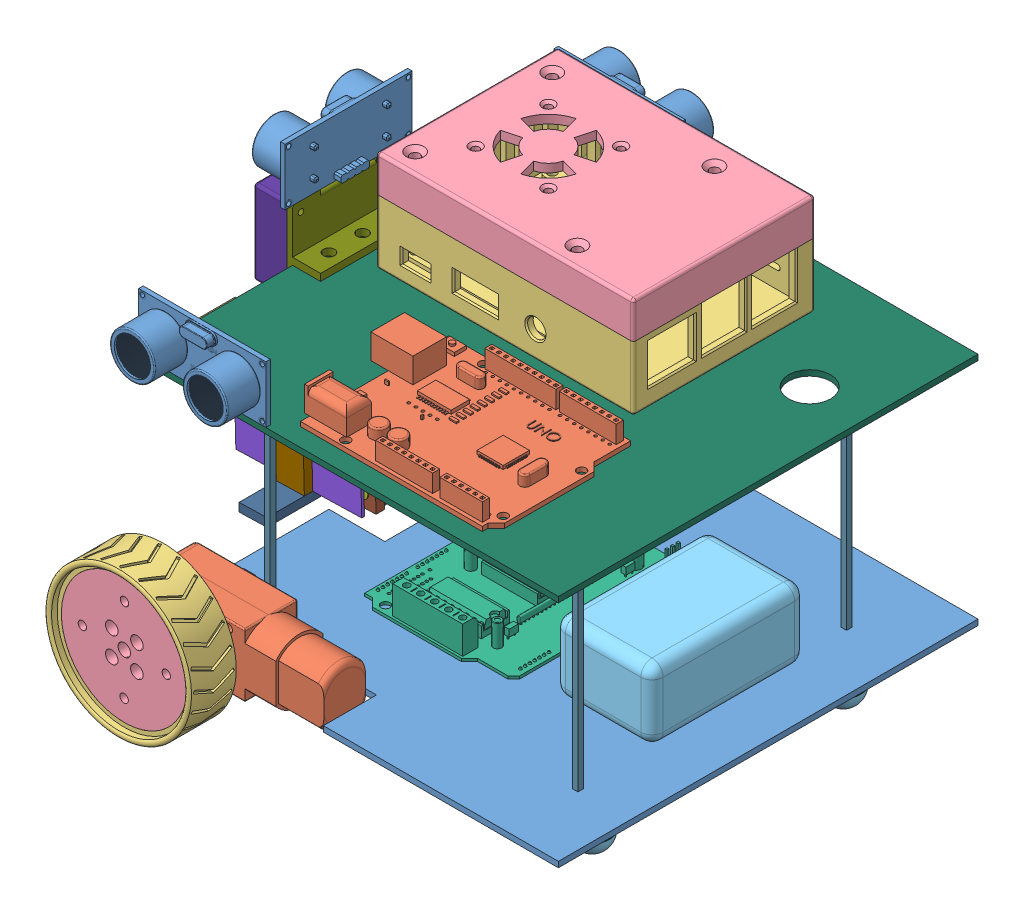
SolidWorks assembly Robo, configuration Default. Lengths in mm.
Overall size (198.95 162.78 193.09).
44 component instances, 24 part files, 52 mates.
Components (placement in the parent):
- Chassie-1: Chassie [Default] at (56.3992 70.6772 119.4071) size (150 2 150)
- wheel-1: wheel [Default] at (-59.9248 68.2072 35.5851) x (0 0 -1) z (0.96637 0.257157 0) size (47.16 66.76 87.56)
  - dc_motor_with_wheel-1: dc_motor_with_wheel [Défaut] at origin size (37.6 36.38 67.23)
  - tyre-1: tyre [Default] at (1.5267 -5.0802 53) x (1 0 0) z (0 0.34528 0.9385) size (16.83 52 52)
  - wheel_3wholes_outerlayer-1: wheel_3wholes_outerlayer [Default] at (7.5267 -5.0802 53) x (0 -0.603955 0.797018) z (0 -0.797018 -0.603955) size (45 4 45)
- wheel-2: wheel [Default] at (-59.9248 85.6472 203.229) x (0 0 1) z (0.96637 -0.257157 0) size (47.16 66.76 87.56)
  - dc_motor_with_wheel-1: dc_motor_with_wheel [Défaut] at origin size (37.6 36.38 67.23)
  - tyre-1: tyre [Default] at (1.5267 -5.0802 53) x (1 0 0) z (0 0.34528 0.9385) size (16.83 52 52)
  - wheel_3wholes_outerlayer-1: wheel_3wholes_outerlayer [Default] at (7.5267 -5.0802 53) x (0 -0.603955 0.797018) z (0 -0.797018 -0.603955) size (45 4 45)
- ball_v2-1: ball_v2 [Default] at (114.5561 64.9929 70.0782) x (-0.994727 0.101202 0.016649) z (0.102116 0.992387 0.068845) size (19.98 29.54 22.65)
  - ball-1: ball [Predeterminado] at (1.5642 3.9174 -7.4116) x (0.97009 -0.147809 -0.192554) z (0.182549 -0.078633 0.980047) size (12.6 12.6 12.6)
  - bas-1: bas [Predeterminado] at (3.6231 4.1003 3.995) x (-0.016649 -0.997488 -0.068845) z (0.994727 -0.009555 -0.102116) size (28.57 12.2 18.37)
- ball_v2-2: ball_v2 [Default] at (114.5561 64.9929 159.8852) x (-0.994727 0.101202 0.016649) z (0.102116 0.992387 0.068845) size (19.98 29.54 22.65)
  - ball-1: ball [Predeterminado] at (1.5642 3.9174 -7.4116) x (0.97009 -0.147809 -0.192554) z (0.182549 -0.078633 0.980047) size (12.6 12.6 12.6)
  - bas-1: bas [Predeterminado] at (3.6231 4.1003 3.995) x (-0.016649 -0.997488 -0.068845) z (0.994727 -0.009555 -0.102116) size (28.57 12.2 18.37)
- gripper-1: gripper [Default] at (95.6972 294.7422 312.9195) x (0.383049 0 0.923728) z (0 -1 0) size (92.65 69.09 65.38)
  - Servo-1: Servo [Default] at (-244.1629 10.2538 215.865) x (0.383049 -0.923728 0) z (0 0 1) size (27.6 29.9 12.4)
  - pad-1: pad [Default] at (-243.8055 16.9469 180.3776) x (-0.010204 0.024608 -0.999645) z (-0.923728 -0.383049 0) size (45 45 1)
  - pad-2: pad [Default] at (-199.6069 35.275 180.3776) x (-0.010204 0.024608 -0.999645) z (0.923728 0.383049 0) size (45 45 1)
  - arm-1: arm [Default] at (-244.7292 16.5638 180.3776) x (-0.010204 0.024608 -0.999645) z (-0.923728 -0.383049 0) size (45 10 3)
  - arm-3: arm [Default] at (-198.6831 35.6581 180.3776) x (-0.010204 0.024608 -0.999645) z (0.923728 0.383049 0) size (45 10 3)
  - Part12^gripper-1: Part12^gripper [Default] at (-220.2923 26.0484 202.8696) x (0.010204 -0.024608 0.999645) z (-0.923728 -0.383049 0) size (3 10 80) (virtual)
  - Part13^gripper-1: Part13^gripper [Default] at (-221.5708 25.2154 213.3659) x (0.923728 0.383049 0) z (0.010204 -0.024608 0.999645) size (3 10 15) (virtual)
  - Part14^gripper-1: Part14^gripper [Default] at (-256.1442 20.5956 158.0854) x (0.923728 0.383049 0) z (-0.382913 0.9234 0.02664) size (20 1 30) (virtual)
  - Part14^gripper-2: Part14^gripper [Default] at (-193.4812 46.6093 157.0858) x (-0.923728 -0.383049 0) z (-0.382913 0.9234 0.02664) size (20 1 30) (virtual)
- IR Sensor-1: IR Sensor [Default] at (11.3992 70.6772 119.4071) x (0 0 1) z (1 0 0) size (110 9 22)
- bar-1: bar [Default] at (2.3992 72.6772 168.4071) size (2 80 2)
- bar-2: bar [Default] at (0.3992 72.6772 70.4071) x (-1 0 0) z (0 0 -1) size (2 80 2)
- bar-4: bar [Default] at (112.3992 72.6772 168.4071) size (2 80 2)
- bar-6: bar [Default] at (110.3992 72.6772 70.4071) x (-1 0 0) z (0 0 -1) size (2 80 2)
- ChassieTop-1: ChassieTop [Default] at (56.3992 152.6772 119.4071) size (150 2 150)
- Cam hosuing Assembly-1: Cam hosuing Assembly [Default] at (-5.1029 127.1366 128.1973) x (0 0 -1) z (0 1 0) size (40 24 30)
  - Camera case bottomV3-1: Camera case bottomV3 [Default] at (8.7902 13.4979 31.0406) size (40 18 30)
  - Camera Case Top-1: Camera Case Top [Default] at (8.7902 25.4979 31.0406) x (1 0 0) z (0 1 0) size (40 30 12)
  - Raspberry Pi-1: Raspberry Pi [Default] at (8.7902 18.4979 31.7906) x (1 0 0) z (0 1 0) size (25 24 8)
- Sensor Ultrasonic-1: Sensor Ultrasonic [Predeterminado] at (4.1092 164.8472 194.4071) size (45.42 20.34 16)
- Sensor Ultrasonic-2: Sensor Ultrasonic [Predeterminado] at (4.1092 164.8472 44.4071) x (-1 0 0) z (0 0 -1) size (45.42 20.34 16)
- Sensor Ultrasonic-3: Sensor Ultrasonic [Predeterminado] at (-20.2008 183.3472 119.4071) x (0 0 1) z (-1 0 0) size (45.42 20.34 16)
- arduino_UNO-1: arduino_UNO [Default] at (32.7088 154.6772 134.9119) size (74.2 10.6 53)
- new assembly-1: new assembly [Default] at (7.8571 132.3466 37.7465) size (92 36 65)
  - enclosure bottom-1: enclosure bottom [Default] at (35.2616 22.3306 87.5788) size (92 28 65)
  - enclosure top-1: enclosure top [Default] at (35.2616 55.3306 55.0788) size (92 13 65)
- battery-1: battery [Default] at (55.734 72.6772 119.8314) x (-1 0 0) z (0 0 -1) size (52.22 25 123.6)
- Part1-1: Part1 [Default] at (41.4025 72.6772 115.5042) x (0 0 1) z (0 1 0) size (68.8 53.3 11.5)
Mates (geometry in assembly coordinates):
- Coincident1: coincident aligned: plane of Chassie-1 through (-18.6008 72.6772 44.4071) normal (-1 0 0); plane of wheel-1/dc_motor_with_wheel-1 through (-18.6008 65.6772 44.6071) normal (-1 0 0)
- Coincident3: coincident anti-aligned: plane of Chassie-1 through (-18.6008 70.6762 63.4071) normal (0 0 -1); plane of wheel-1/dc_motor_with_wheel-1 through (-7.4008 76.9272 63.4071) normal (0 0 1)
- Distance1: distance = 5 mm aligned: plane of Chassie-1 through (56.3992 70.6772 119.4071) normal (0 -1 0); plane of wheel-1/dc_motor_with_wheel-1 through (19.1992 65.6772 44.6071) normal (0 -1 0)
- Coincident5: coincident aligned: plane of Chassie-1 through (-18.6008 72.6772 44.4071) normal (-1 0 0); plane of wheel-2/dc_motor_with_wheel-1 through (-18.6008 88.1772 194.2071) normal (-1 0 0)
- Coincident6: coincident anti-aligned: plane of Chassie-1 through (-18.6008 70.6762 175.4071) normal (0 0 1); plane of wheel-2/dc_motor_with_wheel-1 through (-7.4008 76.9272 175.4071) normal (0 0 -1)
- Distance2: distance = 5 mm aligned: plane of wheel-2/dc_motor_with_wheel-1 through (-18.6008 65.6772 194.2071) normal (0 -1 0); plane of Chassie-1 through (56.3992 70.6772 119.4071) normal (0 -1 0)
- Coincident53: coincident anti-aligned: plane of Chassie-1 through (56.3992 70.6772 119.4071) normal (0 -1 0); plane of ball_v2-1/bas-1 through (117.1358 70.6772 85.4515) normal (0 1 0)
- Coincident55: coincident: line of Chassie-1 through (111.3992 70.6772 194.4071) axis (0 0 -1)
- Coincident56: coincident: line of Chassie-1 through (111.3992 70.6772 194.4071) axis (0 0 -1)
- Distance12: distance = 20 mm: line of assembly; point of ball_v2-1/bas-1; line of Chassie-1 through (131.3992 70.6772 44.4071) axis (-1 0 0)
- Coincident58: coincident anti-aligned: plane of Chassie-1 through (56.3992 70.6772 119.4071) normal (0 -1 0); plane of ball_v2-2/bas-1 through (117.1358 70.6772 175.2585) normal (0 1 0)
- Coincident59: coincident: line of Chassie-1 through (111.3992 70.6772 194.4071) axis (0 0 -1)
- Coincident62: coincident: line of Chassie-1 through (111.3992 70.6772 194.4071) axis (0 0 -1)
- Distance13: distance = 20 mm: line of assembly; point of ball_v2-2/bas-1; line of Chassie-1 through (47.3992 70.6772 194.4071) axis (1 0 0)
- Coincident67: coincident anti-aligned: plane of Chassie-1 through (56.3992 72.6772 119.4071) normal (0 1 0); plane of gripper-1/Servo-1 through (-18.6008 72.6772 113.6071) normal (0 -1 0)
- Coincident68: coincident aligned: plane of Chassie-1 through (-18.6008 72.6772 44.4071) normal (-1 0 0); plane of gripper-1/Servo-1 through (-18.6008 72.6772 113.6071) normal (-1 0 0)
- Distance14: distance = 54.5 mm anti-aligned: plane of wheel-2/dc_motor_with_wheel-1 through (-7.4008 76.9272 175.4071) normal (0 0 -1); plane of gripper-1/Part13^gripper-1 through (-12.4674 81.3763 120.9071) normal (0 0 1)
- Coincident70: coincident anti-aligned: plane of Chassie-1 through (56.3992 70.6772 119.4071) normal (0 -1 0); plane of IR Sensor-1 through (11.3992 70.6772 119.4071) normal (0 1 0)
- Coincident71: coincident aligned: plane of Chassie-1 through (1.3992 70.6762 111.4071) normal (-1 0 0); plane of IR Sensor-1 through (1.3992 68.6772 174.4071) normal (-1 0 0)
- Distance15: distance = 1 mm anti-aligned: plane of wheel-2/dc_motor_with_wheel-1 through (-7.4008 76.9272 175.4071) normal (0 0 -1); plane of IR Sensor-1 through (21.3992 68.6772 174.4071) normal (0 0 1)
- Coincident73: coincident anti-aligned: plane of Chassie-1 through (56.3992 72.6772 119.4071) normal (0 1 0); plane of bar-1 through (2.3992 72.6772 168.4071) normal (0 -1 0)
- Parallel5: parallel aligned: plane of Chassie-1 through (-18.6008 72.6772 194.4071) normal (0 0 1); plane of bar-1 through (1.3992 152.6772 169.4071) normal (0 0 1)
- Coincident75: coincident: line of assembly; point of Chassie-1; line of bar-1 through (1.3992 152.6772 169.4071) axis (0 -1 0)
- Coincident76: coincident anti-aligned: plane of Chassie-1 through (56.3992 72.6772 119.4071) normal (0 1 0); plane of bar-2 through (0.3992 72.6772 70.4071) normal (0 -1 0)
- Parallel6: parallel aligned: plane of Chassie-1 through (-18.6008 72.6772 44.4071) normal (0 0 -1); plane of bar-2 through (1.3992 152.6772 69.4071) normal (0 0 -1)
- Coincident77: coincident: line of assembly; point of Chassie-1; line of bar-2 through (1.3992 152.6772 69.4071) axis (0 -1 0)
- Coincident78: coincident anti-aligned: plane of Chassie-1 through (56.3992 72.6772 119.4071) normal (0 1 0); plane of bar-4 through (112.3992 72.6772 168.4071) normal (0 -1 0)
- Parallel7: parallel aligned: plane of Chassie-1 through (-18.6008 72.6772 194.4071) normal (0 0 1); plane of bar-4 through (111.3992 152.6772 169.4071) normal (0 0 1)
- Coincident79: coincident: line of assembly; point of Chassie-1; line of bar-4 through (111.3992 152.6772 169.4071) axis (0 -1 0)
- Coincident80: coincident anti-aligned: plane of Chassie-1 through (56.3992 72.6772 119.4071) normal (0 1 0); plane of bar-6 through (110.3992 72.6772 70.4071) normal (0 -1 0)
- Parallel8: parallel aligned: plane of Chassie-1 through (-18.6008 72.6772 44.4071) normal (0 0 -1); plane of bar-6 through (111.3992 152.6772 69.4071) normal (0 0 -1)
- Coincident81: coincident: line of assembly; point of Chassie-1; line of bar-6 through (111.3992 152.6772 69.4071) axis (0 -1 0)
- Coincident87: coincident anti-aligned: plane of bar-1 through (2.3992 152.6772 168.4071) normal (0 1 0); plane of ChassieTop-1 through (56.3992 152.6772 119.4071) normal (0 -1 0)
- Coincident88: coincident aligned: plane of Chassie-1 through (-18.6008 72.6772 194.4071) normal (0 0 1); plane of ChassieTop-1 through (-18.6008 154.6772 194.4071) normal (0 0 1)
- Coincident89: coincident aligned: plane of Chassie-1 through (-18.6008 72.6772 44.4071) normal (-1 0 0); plane of ChassieTop-1 through (-18.6008 154.6772 44.4071) normal (-1 0 0)
- Coincident90: coincident anti-aligned: plane of ChassieTop-1 through (56.3992 154.6772 119.4071) normal (0 1 0); plane of Cam hosuing Assembly-1/Camera case bottomV3-1 through (-8.6008 154.6772 139.4071) normal (0 -1 0)
- Coincident91: coincident anti-aligned: plane of ChassieTop-1 through (-18.6008 154.6772 44.4071) normal (-1 0 0); plane of Cam hosuing Assembly-1/Camera case bottomV3-1 through (-18.6008 158.1772 119.4071) normal (1 0 0)
- Distance16: distance = 55 mm aligned: plane of ChassieTop-1 through (-18.6008 154.6772 194.4071) normal (0 0 1); plane of Cam hosuing Assembly-1/Camera case bottomV3-1 through (-20.6008 143.1772 139.4071) normal (0 0 1)
- Coincident93: coincident anti-aligned: plane of ChassieTop-1 through (56.3992 154.6772 119.4071) normal (0 1 0); plane of Sensor Ultrasonic-1 through (-18.6008 154.6772 192.8071) normal (0 -1 0)
- Coincident94: coincident aligned: plane of ChassieTop-1 through (-18.6008 154.6772 194.4071) normal (0 0 1); plane of Sensor Ultrasonic-1 through (4.1092 164.8472 194.4071) normal (0 0 1)
- Coincident95: coincident aligned: plane of ChassieTop-1 through (-18.6008 154.6772 44.4071) normal (-1 0 0); plane of Sensor Ultrasonic-1 through (-18.6008 154.6772 192.8071) normal (-1 0 0)
- Coincident96: coincident anti-aligned: plane of ChassieTop-1 through (56.3992 154.6772 119.4071) normal (0 1 0); plane of Sensor Ultrasonic-2 through (26.8192 154.6772 46.0071) normal (0 -1 0)
- Coincident97: coincident aligned: plane of ChassieTop-1 through (-18.6008 154.6772 44.4071) normal (0 0 -1); plane of Sensor Ultrasonic-2 through (4.1092 164.8472 44.4071) normal (0 0 -1)
- Coincident98: coincident aligned: plane of ChassieTop-1 through (-18.6008 154.6772 44.4071) normal (-1 0 0); plane of Sensor Ultrasonic-2 through (-18.6008 154.6772 46.0071) normal (-1 0 0)
- Coincident102: coincident anti-aligned: plane of Cam hosuing Assembly-1/Camera case bottomV3-1 through (-20.6008 173.1772 139.4071) normal (0 1 0); plane of Sensor Ultrasonic-3 through (-18.6008 173.1772 96.6971) normal (0 -1 0)
- Coincident103: coincident aligned: plane of Cam hosuing Assembly-1/Camera case bottomV3-1 through (-18.6008 158.1772 119.4071) normal (1 0 0); plane of Sensor Ultrasonic-3 through (-18.6008 183.3472 119.4071) normal (1 0 0)
- Distance17: distance = 52.29 mm aligned: plane of Sensor Ultrasonic-3 through (-18.6008 173.1772 142.1171) normal (0 0 1); plane of ChassieTop-1 through (-18.6008 154.6772 194.4071) normal (0 0 1)
- Coincident111: coincident anti-aligned: plane of ChassieTop-1 through (56.3992 154.6772 119.4071) normal (0 1 0); plane of new assembly-1/enclosure bottom-1 through (43.1186 154.6772 125.3253) normal (0 -1 0)
- Coincident113: coincident anti-aligned: plane of Chassie-1 through (56.3992 72.6772 119.4071) normal (0 1 0); plane of battery-1 through (55.734 72.6772 119.8314) normal (0 -1 0)
- Coincident116: coincident anti-aligned: plane of Chassie-1 through (56.3992 72.6772 119.4071) normal (0 1 0); plane of Part1-1 through (41.4025 72.6772 115.5042) normal (0 -1 0)
- Coincident119: coincident anti-aligned: plane of ChassieTop-1 through (56.3992 154.6772 119.4071) normal (0 1 0); plane of arduino_UNO-1 through (32.7088 154.6772 134.9119) normal (0 -1 0)
- Parallel15: parallel anti-aligned: plane of Chassie-1 through (-18.6008 72.6772 44.4071) normal (0 0 -1); plane of battery-1 through (114.144 97.6772 143.6794) normal (0 0 1)
